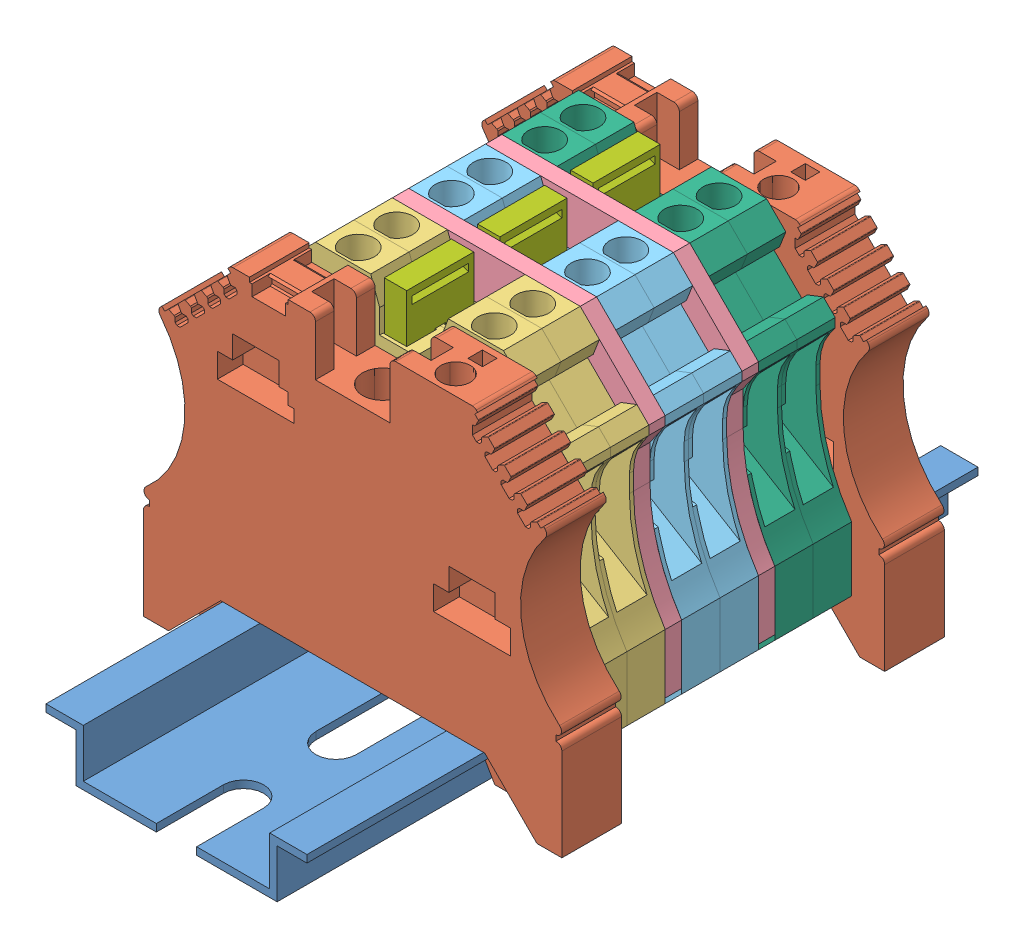
SolidWorks assembly Verteilung Bett, configuration Standard. Lengths in mm.
Overall size (56.38 56.59 90).
14 component instances, 7 part files, 54 mates.
Components (placement in the parent):
- Hutschiene-1: Hutschiene [090] at (-17.5 0 -90) size (35 7.5 90)
- WEW_35_2-1: WEW_35_2 [Standard] at (-45.61 0.5 -31.7) x (0 0 1) z (0 1 0) size (8 56.1 46.5)
- UT_2.5_PE-1: UT_2.5_PE [Standard] at (-49.1489 18.1178 -31.7) x (0.992546 -0.121869 0) z (0 0 1) size (49.27 50.96 5.15)
- UT_2.5_PE-2: UT_2.5_PE [Standard] at (-49.1489 18.1178 -36.85) x (0.992546 -0.121869 0) z (0 0 1) size (49.27 50.96 5.15)
- D_UT_2.5_10-2: D_UT_2.5_10 [Standard] at (-46.8797 65.95 -44.2) size (47 39.8 2.2)
- UT_2.5_BU-1: UT_2.5_BU [Standard] at (-49.1489 18.1178 -44.2) x (0.992546 -0.121869 0) z (0 0 1) size (49.27 50.96 5.15)
- UT_2.5_BU-2: UT_2.5_BU [Standard] at (-49.1489 18.1178 -49.35) x (0.992546 -0.121869 0) z (0 0 1) size (49.27 50.96 5.15)
- D_UT_2.5_10-3: D_UT_2.5_10 [Standard] at (-46.8797 65.95 -56.7) size (47 39.8 2.2)
- UT_2.5-1: UT_2.5 [Standard] at (-49.1489 18.1178 -56.7) x (0.992546 -0.121869 0) z (0 0 1) size (49.27 50.96 5.15)
- UT_2.5-2: UT_2.5 [Standard] at (-49.1489 18.1178 -61.85) x (0.992546 -0.121869 0) z (0 0 1) size (49.27 50.96 5.15)
- WEW_35_2-3: WEW_35_2 [Standard] at (-45.61 0.5 -75) x (0 0 1) z (0 1 0) size (8 56.1 46.5)
- FBS_2-5-1: FBS_2-5 [Standard] at (-24.4072 56.675 -90.535) size (3 22.98 9)
- FBS_2-5-2: FBS_2-5 [Standard] at (-24.4072 56.675 -103.035) size (3 22.98 9)
- FBS_2-5-3: FBS_2-5 [Standard] at (-24.4072 56.675 -115.535) size (3 22.98 9)
Mates (geometry in assembly coordinates):
- Deckungsgleich2: coincident anti-aligned: plane of Hutschiene-1 through (-31 0 0) normal (0 -1 0); plane of assembly through (0 0 0) normal (0 1 0)
- Deckungsgleich3: coincident aligned: plane of Hutschiene-1 through (-17.5 0 0) normal (0 0 1); plane of assembly through (0 0 0) normal (0 0 1)
- Deckungsgleich4: coincident aligned: plane of Hutschiene-1 through (0 6.5 0) normal (1 0 0); plane of assembly through (0 0 0) normal (1 0 0)
- Deckungsgleich5: coincident anti-aligned: plane of Hutschiene-1 through (0 7.5 0) normal (0 1 0); plane of ? through (0.14 7.5 -18.55) normal (0 -1 0)
- Deckungsgleich6: coincident anti-aligned: plane of ? through (-30 7.5 0) normal (0 1 0); plane of ? through (-32.7417 7.5 -70.1851) normal (0 -1 0)
- Tangential1: tangent anti-aligned: plane of Hutschiene-1 through (0 6.5 0) normal (1 0 0); cylinder of ? through (2 6.1 -22.55) axis (0 0 1) radius 2
- Deckungsgleich8: coincident anti-aligned: plane of ? through (-17.56 7.5 -24.35) normal (0 0 -1); plane of ? through (-31.8034 38.831 -24.35) normal (0 0 1)
- Deckungsgleich9: coincident anti-aligned: plane of ? through (8.476 3.72 -26.55) normal (0 0 -1); plane of ? through (-0.45 7.5 -26.55) normal (0 0 1)
- Deckungsgleich10: coincident anti-aligned: plane of ? through (-0.45 7.5 -31.7) normal (0 0 -1); plane of UT_2.5_PE-1 through (-0.45 7.5 -31.7) normal (0 0 1)
- Deckungsgleich11: coincident anti-aligned: plane of UT_2.5_PE-1 through (-0.45 7.5 -36.85) normal (0 0 -1); plane of ? through (-31.8034 38.831 -36.85) normal (0 0 1)
- Deckungsgleich12: coincident anti-aligned: plane of ? through (8.476 3.72 -39.05) normal (0 0 -1); plane of ? through (-0.45 7.5 -39.05) normal (0 0 1)
- Deckungsgleich13: coincident anti-aligned: plane of ? through (-0.45 7.5 -44.2) normal (0 0 -1); plane of UT_2.5_BU-1 through (-0.45 7.5 -44.2) normal (0 0 1)
- Deckungsgleich14: coincident anti-aligned: plane of UT_2.5_BU-1 through (-0.45 7.5 -49.35) normal (0 0 -1); plane of ? through (-31.8034 38.831 -49.35) normal (0 0 1)
- Deckungsgleich15: coincident anti-aligned: plane of ? through (8.476 3.72 -51.55) normal (0 0 -1); plane of ? through (-0.45 7.5 -51.55) normal (0 0 1)
- Deckungsgleich16: coincident anti-aligned: plane of ? through (-0.45 7.5 -56.7) normal (0 0 -1); plane of ? through (4.2582 9.6963 -61.8499) normal (0 0 1)
- Deckungsgleich17: coincident anti-aligned: plane of UT_2.5-1 through (-0.45 7.5 -61.85) normal (0 0 -1); plane of UT_2.5-2 through (-0.45 7.5 -61.85) normal (0 0 1)
- Deckungsgleich18: coincident anti-aligned: plane of UT_2.5-2 through (-0.45 7.5 -67) normal (0 0 -1); plane of WEW_35_2-3 through (-17.56 7.5 -67) normal (0 0 1)
- Deckungsgleich19: coincident anti-aligned: plane of Hutschiene-1 through (-30 7.5 0) normal (0 1 0); plane of ? through (-8.15 7.5 -26.55) normal (0 -1 0)
- Deckungsgleich20: coincident anti-aligned: plane of Hutschiene-1 through (-30 7.5 0) normal (0 1 0); plane of UT_2.5_PE-1 through (-8.15 7.5 -31.7) normal (0 -1 0)
- Deckungsgleich21: coincident anti-aligned: plane of Hutschiene-1 through (-30 7.5 0) normal (0 1 0); plane of ? through (-8.15 7.5 -39.05) normal (0 -1 0)
- Deckungsgleich22: coincident anti-aligned: plane of Hutschiene-1 through (-30 7.5 0) normal (0 1 0); plane of UT_2.5_BU-1 through (-8.15 7.5 -44.2) normal (0 -1 0)
- Deckungsgleich23: coincident anti-aligned: plane of Hutschiene-1 through (-30 7.5 0) normal (0 1 0); plane of ? through (-8.15 7.5 -51.55) normal (0 -1 0)
- Deckungsgleich24: coincident anti-aligned: plane of Hutschiene-1 through (-30 7.5 0) normal (0 1 0); plane of ? through (-3.4418 9.6963 -61.8499) normal (0 -1 0)
- Deckungsgleich25: coincident anti-aligned: plane of Hutschiene-1 through (-30 7.5 0) normal (0 1 0); plane of UT_2.5-2 through (-8.15 7.5 -61.85) normal (0 -1 0)
- Deckungsgleich26: coincident anti-aligned: plane of Hutschiene-1 through (-30 7.5 0) normal (0 1 0); plane of WEW_35_2-3 through (0.14 7.5 -67) normal (0 -1 0)
- Deckungsgleich27: coincident anti-aligned: plane of Hutschiene-1 through (-35 7.5 0) normal (-1 0 0); plane of ? through (-35 6.9 -28.525) normal (1 0 0)
- Deckungsgleich28: coincident aligned: plane of ? through (6.05 15.6559 -26.55) normal (1 0 0); plane of UT_2.5_PE-1 through (6.05 15.6559 -31.7) normal (1 0 0)
- Deckungsgleich29: coincident aligned: plane of ? through (-5.35 47.5 -25.45) normal (0.707107 0.707107 0); plane of ? through (-5.35 47.5 -26.55) normal (0.707107 0.707107 0)
- Deckungsgleich30: coincident aligned: plane of ? through (-23.15 47.5 -24.95) normal (0 1 0); plane of ? through (-12.75 47.5 -26.55) normal (0 1 0)
- Deckungsgleich31: coincident aligned: plane of UT_2.5_PE-1 through (-5.35 47.5 -31.7) normal (0.707107 0.707107 0); plane of ? through (-5.35 47.5 -37.95) normal (0.707107 0.707107 0)
- Deckungsgleich32: coincident aligned: plane of UT_2.5_PE-1 through (-12.75 47.5 -31.7) normal (0 1 0); plane of ? through (-23.15 47.5 -37.45) normal (0 1 0)
- Deckungsgleich33: coincident aligned: plane of UT_2.5_PE-1 through (6.05 15.6559 -31.7) normal (1 0 0); plane of ? through (6.05 15.6559 -39.05) normal (1 0 0)
- Deckungsgleich34: coincident aligned: plane of ? through (6.05 15.6559 -39.05) normal (1 0 0); plane of UT_2.5_BU-1 through (6.05 15.6559 -44.2) normal (1 0 0)
- Deckungsgleich35: coincident aligned: plane of UT_2.5_BU-1 through (-5.35 47.5 -44.2) normal (0.707107 0.707107 0); plane of ? through (-5.35 47.5 -50.45) normal (0.707107 0.707107 0)
- Deckungsgleich36: coincident aligned: plane of UT_2.5_BU-1 through (-12.75 47.5 -44.2) normal (0 1 0); plane of ? through (-23.15 47.5 -49.95) normal (0 1 0)
- Deckungsgleich37: coincident aligned: plane of UT_2.5_BU-1 through (6.05 15.6559 -44.2) normal (1 0 0); plane of ? through (6.05 15.6559 -51.55) normal (1 0 0)
- Deckungsgleich38: coincident aligned: plane of ? through (6.05 15.6559 -51.55) normal (1 0 0); plane of ? through (10.7582 17.8522 -61.8499) normal (1 0 0)
- Deckungsgleich39: coincident aligned: plane of UT_2.5-1 through (6.05 15.6559 -56.7) normal (1 0 0); plane of UT_2.5-2 through (6.05 15.6559 -61.85) normal (1 0 0)
- Deckungsgleich40: coincident aligned: plane of ? through (10.49 0.5 -18.55) normal (1 0 0); plane of WEW_35_2-3 through (10.49 0.5 -67) normal (1 0 0)
- Abstand1: distance = 15 mm aligned: plane of WEW_35_2-3 through (-17.56 7.5 -75) normal (0 0 -1); plane of Hutschiene-1 through (-17.5 0 -90) normal (0 0 -1)
- Deckungsgleich42: coincident anti-aligned: plane of ? through (-18.8 29.35 -27.025) normal (0 0 -1); plane of ? through (-18.8 47.2 -27.025) normal (0 0 1)
- Deckungsgleich43: coincident anti-aligned: plane of ? through (-18.8 29.35 -39.525) normal (0 0 -1); plane of ? through (-18.8 47.2 -39.525) normal (0 0 1)
- Deckungsgleich44: coincident anti-aligned: plane of ? through (-18.8 29.35 -52.025) normal (0 0 -1); plane of ? through (-18.8 47.5 -52.025) normal (0 0 1)
- Deckungsgleich45: coincident anti-aligned: plane of ? through (-18.8 29.35 -56.05) normal (-1 0 0); plane of ? through (-18.8 49.4423 -26.765) normal (1 0 0)
- Deckungsgleich46: coincident anti-aligned: plane of ? through (-18.8 29.35 -43.55) normal (-1 0 0); plane of ? through (-18.8 46.2586 -48.2595) normal (1 0 0)
- Deckungsgleich47: coincident anti-aligned: plane of ? through (-18.8 29.35 -31.05) normal (-1 0 0); plane of ? through (-18.8 46.2586 -35.7595) normal (1 0 0)
- Deckungsgleich48: coincident aligned: plane of ? through (-30.55 47.5 -26.55) normal (0 1 0); plane of ? through (-18.8 47.5 -6.525) normal (0 1 0)
- Deckungsgleich49: coincident aligned: plane of ? through (-30.55 47.5 -39.05) normal (0 1 0); plane of ? through (-18.8 47.5 -19.025) normal (0 1 0)
- Deckungsgleich50: coincident aligned: plane of ? through (-30.55 47.5 -51.55) normal (0 1 0); plane of ? through (-18.8 47.5 -66.225) normal (0 1 0)
- Deckungsgleich51: coincident anti-aligned: plane of ? through (-17.56 7.5 -26.55) normal (0 0 -1); plane of ? through (-0.45 7.5 -26.55) normal (0 0 1)
- Deckungsgleich52: coincident anti-aligned: plane of UT_2.5-2 through (-0.45 7.5 -67) normal (0 0 -1); plane of WEW_35_2-3 through (-17.56 7.5 -67) normal (0 0 1)
- Deckungsgleich53: coincident: plane of FBS_2-5-1 through (-18.8 47.5 -11.675) normal (0 1 0); plane of FBS_2-5-3 through (-18.8 47.5 -36.675) normal (0 1 0)
- Deckungsgleich54: coincident: plane of FBS_2-5-1 through (-18.8 46.2586 -40.9095) normal (1 0 0); plane of FBS_2-5-3 through (-18.8 46.2586 -65.9095) normal (1 0 0)
- Deckungsgleich55: coincident anti-aligned: plane of UT_2.5-1 through (-18.8 29.35 -57.175) normal (0 0 -1); plane of FBS_2-5-3 through (-18.8 47.2 -57.175) normal (0 0 1)
